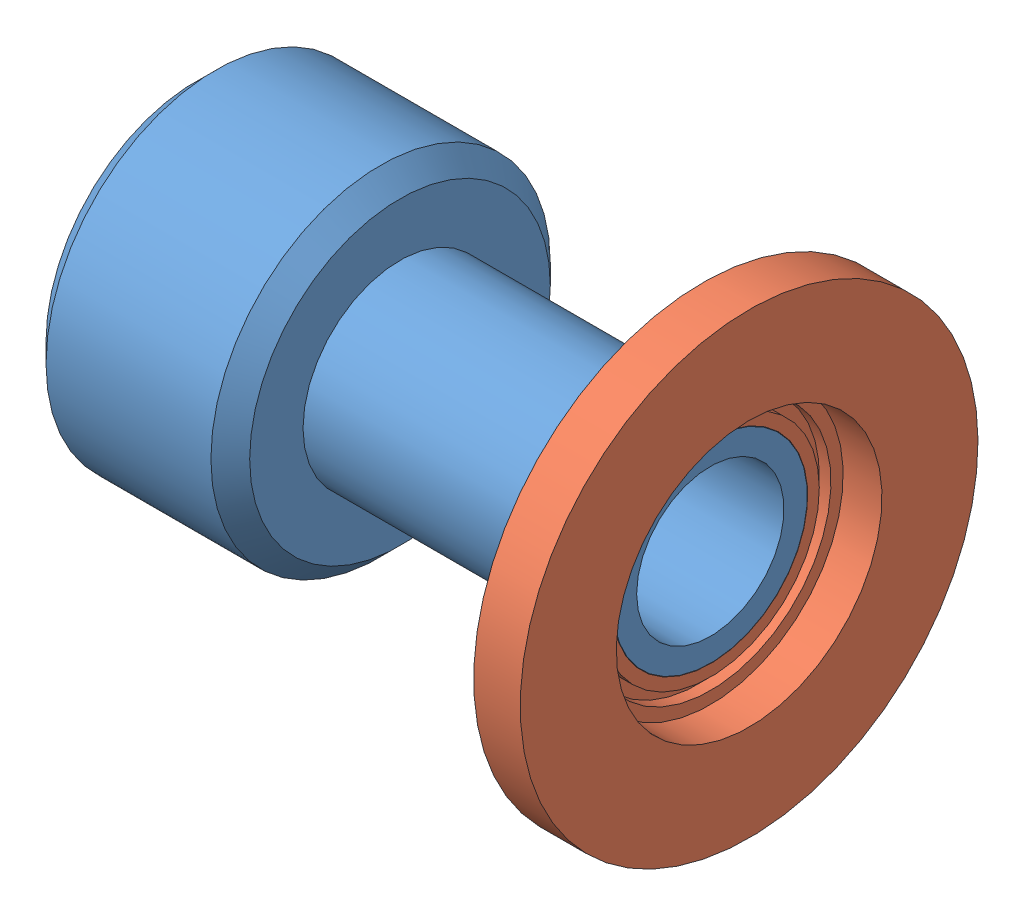
SolidWorks assembly 734005, configuration Default. Lengths in mm.
Overall size (36.2 39.15 39.15).
2 component instances, 2 part files, 2 mates.
Components (placement in the parent):
- 410005-1: 410005 [Default] at (-5.7861 19.6688 26.5453) size (33.65 22.23 22.23)
- 713006-1: 713006 [Default] at (30.4089 19.6688 26.5453) x (0 0.381849 -0.924225) z (0 -0.924225 -0.381849) size (29.97 5.08 29.97)
Mates (geometry in assembly coordinates):
- Coincident1: coincident aligned: plane of 410005-1 through (27.8689 26.0188 26.5453) normal (1 0 0); plane of 713006-1 through (27.8689 22.1032 20.653) normal (1 0 0)
- Concentric1: concentric anti-aligned: cylinder of 410005-1 through (-5.7861 19.6688 26.5453) axis (-1 0 0) radius 6.35; cylinder of 713006-1 through (30.4089 19.6688 26.5453) axis (1 0 0) radius 8.6995
